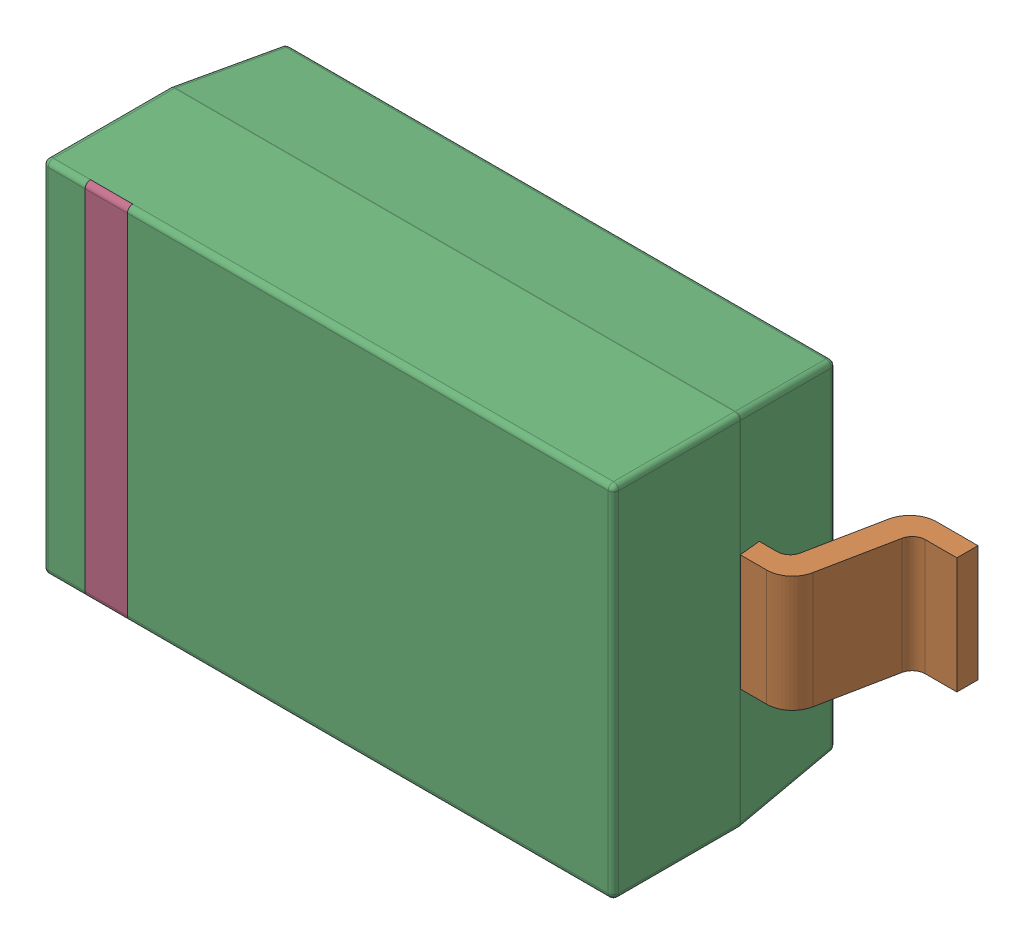
SolidWorks assembly sod123_v4, configuration Default. Lengths in mm.
Overall size (3.75 1.71 1.2).
4 component instances, 4 part files, 0 mates.
Components (placement in the parent):
- pin-1: pin [Default] at (-0.675 -0.875 0) x (0 -1 0) z (0 0 1) size (0.55 0.55 0.6)
- pin(Mirror)-1: pin(Mirror) [Default] at (0.675 -0.875 0) x (0 -1 0) z (0 0 -1) size (0.55 0.55 0.6)
- icbody-1: icbody [Default] at origin size (2.71 1.71 1.11)
- Component5-1: Component5 [Default] at origin size (0.2 1.7 0.02)
